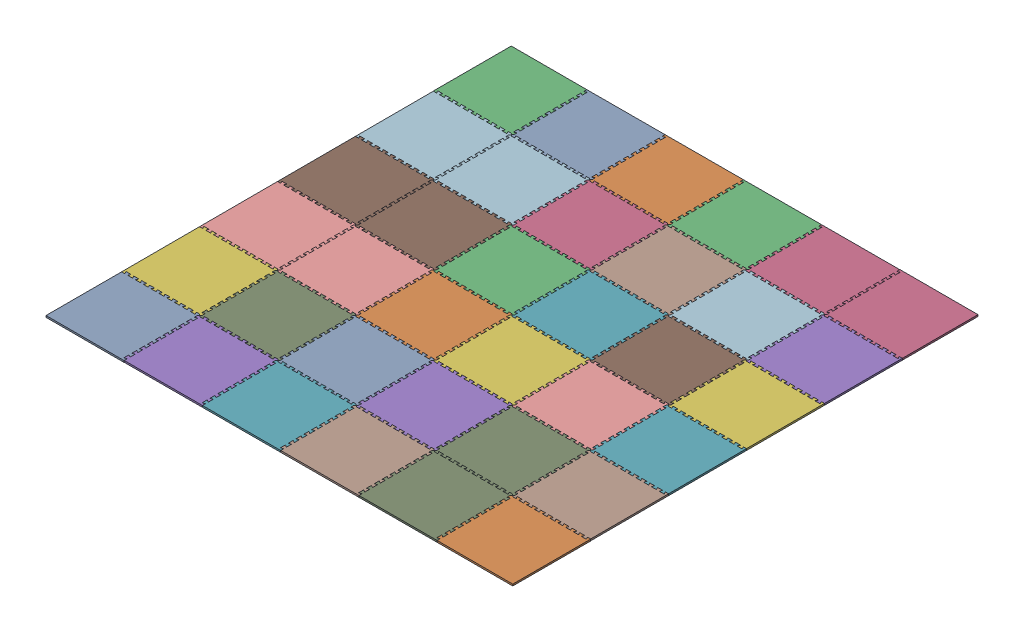
SolidWorks assembly FIELD_RelicRecovery_Tile Field, configuration Default. Lengths in mm.
Overall size (3603.71 12.7 3603.65).
36 component instances, 3 part files, 0 mates.
Components (placement in the parent):
- FIELD_RelicRecovery_Corner soft tile-1: FIELD_RelicRecovery_Corner soft tile [Default] at (291.8914 -12.7 -291.8914) size (602.83 12.7 602.83)
- FIELD_RelicRecovery_Corner soft tile-2: FIELD_RelicRecovery_Corner soft tile [Default] at (3306.0551 -12.7 -297.6546) x (0 0 -1) z (1 0 0) size (602.83 12.7 602.83)
- FIELD_RelicRecovery_Corner soft tile-3: FIELD_RelicRecovery_Corner soft tile [Default] at (286.1281 -12.7 -3306.0551) x (0 0 1) z (-1 0 0) size (602.83 12.7 602.83)
- FIELD_RelicRecovery_Corner soft tile-4: FIELD_RelicRecovery_Corner soft tile [Default] at (3300.2918 -12.7 -3311.7596) x (-1 0 0) z (0 0 -1) size (602.83 12.7 602.83)
- FIELD_RelicRecovery_Side soft tile-1: FIELD_RelicRecovery_Side soft tile [Default] at (894.7241 -12.7 -293.0469) size (621.88 12.7 602.83)
- FIELD_RelicRecovery_Side soft tile-2: FIELD_RelicRecovery_Side soft tile [Default] at (290.7358 -12.7 -894.7241) x (0 0 1) z (-1 0 0) size (621.88 12.7 602.83)
- FIELD_RelicRecovery_Side soft tile-3: FIELD_RelicRecovery_Side soft tile [Default] at (1497.5568 -12.7 -294.2025) size (621.88 12.7 602.83)
- FIELD_RelicRecovery_Side soft tile-4: FIELD_RelicRecovery_Side soft tile [Default] at (2100.3896 -12.7 -295.3581) size (621.88 12.7 602.83)
- FIELD_RelicRecovery_Side soft tile-5: FIELD_RelicRecovery_Side soft tile [Default] at (2703.2223 -12.7 -296.5137) size (621.88 12.7 602.83)
- FIELD_RelicRecovery_Side soft tile-6: FIELD_RelicRecovery_Side soft tile [Default] at (289.5802 -12.7 -1497.5568) x (0 0 1) z (-1 0 0) size (621.88 12.7 602.83)
- FIELD_RelicRecovery_Side soft tile-7: FIELD_RelicRecovery_Side soft tile [Default] at (288.4246 -12.7 -2100.3896) x (0 0 1) z (-1 0 0) size (621.88 12.7 602.83)
- FIELD_RelicRecovery_Side soft tile-8: FIELD_RelicRecovery_Side soft tile [Default] at (287.2691 -12.7 -2703.2223) x (0 0 1) z (-1 0 0) size (621.88 12.7 602.83)
- FIELD_RelicRecovery_Side soft tile-9: FIELD_RelicRecovery_Side soft tile [Default] at (888.9609 -12.7 -3307.196) x (-1 0 0) z (0 0 -1) size (621.88 12.7 602.83)
- FIELD_RelicRecovery_Side soft tile-10: FIELD_RelicRecovery_Side soft tile [Default] at (1491.7936 -12.7 -3308.3369) x (-1 0 0) z (0 0 -1) size (621.88 12.7 602.83)
- FIELD_RelicRecovery_Side soft tile-11: FIELD_RelicRecovery_Side soft tile [Default] at (2094.6264 -12.7 -3309.4778) x (-1 0 0) z (0 0 -1) size (621.88 12.7 602.83)
- FIELD_RelicRecovery_Side soft tile-12: FIELD_RelicRecovery_Side soft tile [Default] at (2697.4591 -12.7 -3310.6187) x (-1 0 0) z (0 0 -1) size (621.88 12.7 602.83)
- FIELD_RelicRecovery_Side soft tile-13: FIELD_RelicRecovery_Side soft tile [Default] at (3301.4327 -12.7 -2708.9269) x (0 0 -1) z (1 0 0) size (621.88 12.7 602.83)
- FIELD_RelicRecovery_Side soft tile-14: FIELD_RelicRecovery_Side soft tile [Default] at (3302.5737 -12.7 -2106.0942) x (0 0 -1) z (1 0 0) size (621.88 12.7 602.83)
- FIELD_RelicRecovery_Side soft tile-15: FIELD_RelicRecovery_Side soft tile [Default] at (3303.7146 -12.7 -1503.2614) x (0 0 -1) z (1 0 0) size (621.88 12.7 602.83)
- FIELD_RelicRecovery_Side soft tile-16: FIELD_RelicRecovery_Side soft tile [Default] at (3304.8555 -12.7 -900.4287) x (0 0 -1) z (1 0 0) size (621.88 12.7 602.83)
- FIELD_RelicRecovery_Standard soft tile-1: FIELD_RelicRecovery_Standard soft tile [Default] at (893.5685 -12.7 -895.8797) size (621.88 12.7 621.88)
- FIELD_RelicRecovery_Standard soft tile-2: FIELD_RelicRecovery_Standard soft tile [Default] at (892.413 -12.7 -1498.7124) size (621.88 12.7 621.88)
- FIELD_RelicRecovery_Standard soft tile-3: FIELD_RelicRecovery_Standard soft tile [Default] at (891.2574 -12.7 -2101.5452) size (621.88 12.7 621.88)
- FIELD_RelicRecovery_Standard soft tile-4: FIELD_RelicRecovery_Standard soft tile [Default] at (890.1018 -12.7 -2704.3779) size (621.88 12.7 621.88)
- FIELD_RelicRecovery_Standard soft tile-5: FIELD_RelicRecovery_Standard soft tile [Default] at (1496.4013 -12.7 -897.0353) size (621.88 12.7 621.88)
- FIELD_RelicRecovery_Standard soft tile-6: FIELD_RelicRecovery_Standard soft tile [Default] at (1495.2457 -12.7 -1499.868) size (621.88 12.7 621.88)
- FIELD_RelicRecovery_Standard soft tile-7: FIELD_RelicRecovery_Standard soft tile [Default] at (1494.0901 -12.7 -2102.7007) size (621.88 12.7 621.88)
- FIELD_RelicRecovery_Standard soft tile-8: FIELD_RelicRecovery_Standard soft tile [Default] at (1492.9345 -12.7 -2705.5335) size (621.88 12.7 621.88)
- FIELD_RelicRecovery_Standard soft tile-9: FIELD_RelicRecovery_Standard soft tile [Default] at (2099.234 -12.7 -898.1908) size (621.88 12.7 621.88)
- FIELD_RelicRecovery_Standard soft tile-10: FIELD_RelicRecovery_Standard soft tile [Default] at (2098.0784 -12.7 -1501.0236) size (621.88 12.7 621.88)
- FIELD_RelicRecovery_Standard soft tile-11: FIELD_RelicRecovery_Standard soft tile [Default] at (2096.9228 -12.7 -2103.8563) size (621.88 12.7 621.88)
- FIELD_RelicRecovery_Standard soft tile-12: FIELD_RelicRecovery_Standard soft tile [Default] at (2095.7673 -12.7 -2706.689) size (621.88 12.7 621.88)
- FIELD_RelicRecovery_Standard soft tile-13: FIELD_RelicRecovery_Standard soft tile [Default] at (2702.0667 -12.7 -899.3464) size (621.88 12.7 621.88)
- FIELD_RelicRecovery_Standard soft tile-14: FIELD_RelicRecovery_Standard soft tile [Default] at (2700.9112 -12.7 -1502.1791) size (621.88 12.7 621.88)
- FIELD_RelicRecovery_Standard soft tile-15: FIELD_RelicRecovery_Standard soft tile [Default] at (2699.7556 -12.7 -2105.0119) size (621.88 12.7 621.88)
- FIELD_RelicRecovery_Standard soft tile-16: FIELD_RelicRecovery_Standard soft tile [Default] at (2698.6 -12.7 -2707.8446) size (621.88 12.7 621.88)
